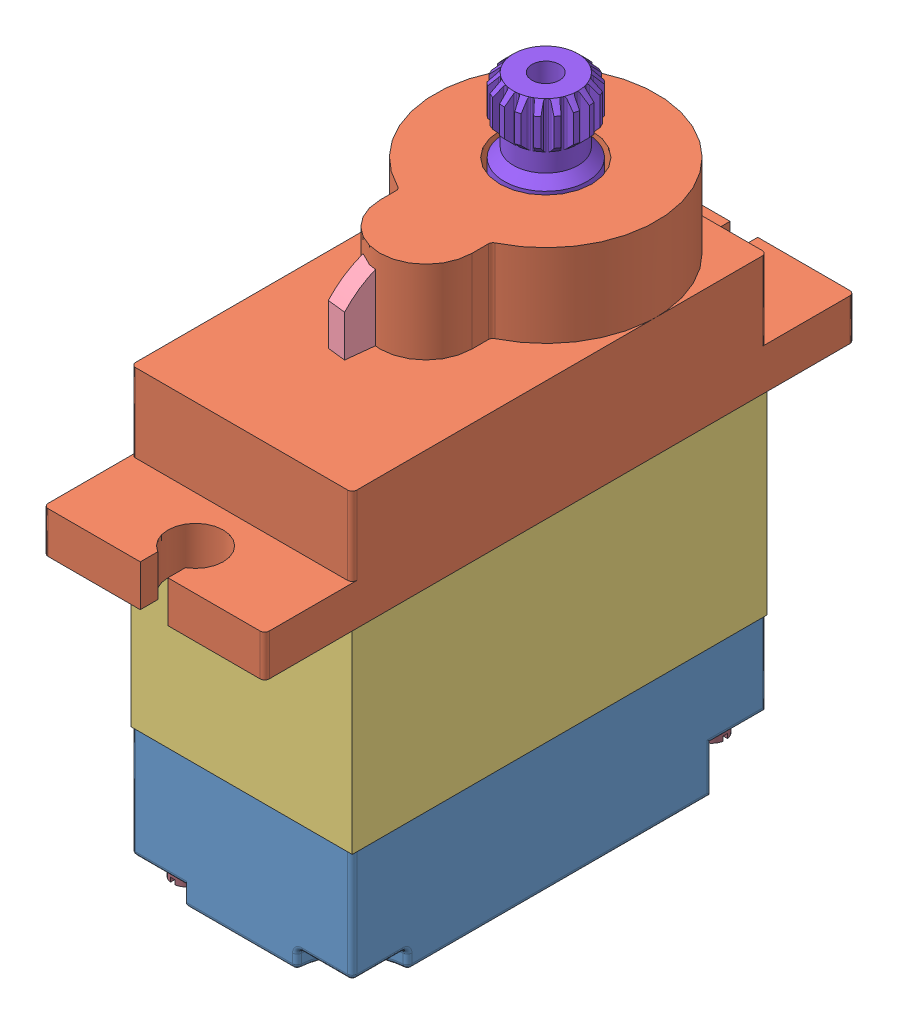
SolidWorks assembly MG90S, configuration Default. Lengths in mm.
Overall size (12 32.5 32).
19 component instances, 13 part files, 49 mates.
Components (placement in the parent):
- Part1-1: Part1 [Default] at (21.0878 -43.0505 -32.5824) x (0 0 -1) z (1 0 0) size (22.54 9 12)
- Part2-1: Part2 [Default] at (21.0878 -25.5505 -32.5824) x (0 0 -1) z (1 0 0) size (32 13 12)
- Part3-1: Part3 [Default] at (21.0878 -36.0505 -32.5824) x (0 0 -1) z (1 0 0) size (22.5 16 12)
- Motor_Body2-2: Motor_Body2 [Default] at (21.0878 -22.3005 -37.8324) x (0 -1 0) z (0.87496 0 0.484196) size (10 2 8)
- Motor_Body2-3: Motor_Body2 [Default] at (21.0878 -19.8005 -31.3324) x (0 -1 0) z (0.109568 0 -0.993979) size (10 2 8)
- Motor_Body2-6: Motor_Body2 [Default] at (21.0878 -19.8005 -37.8324) x (0 1 0) z (-0.993238 0 0.116099) size (10 2 8)
- Motor_Body2-7: Motor_Body2 [Default] at (21.0878 -25.0505 -31.3324) x (0 1 0) z (0.977188 0 0.212376) size (10 2 8)
- Motor_Body2-8: Motor_Body2 [Default] at (21.0878 -23.8005 -31.3324) x (0 1 0) z (0.977188 0 0.212376) size (10 2 8)
- gear3-1: gear3 [Default] at (21.0878 -22.3005 -37.8324) x (0.87496 0 0.484196) z (-0.484196 0 0.87496) size (3.98 2.5 3.92)
- gear1-2: gear1 [Default] at (21.0878 -19.8005 -31.3324) x (0.109568 0 -0.993979) z (0.993979 0 0.109568) size (3.96 2.5 3.87)
- gear2-2: gear2 [Default] at (21.0878 -26.3005 -26.3324) x (0.891105 0 -0.453797) z (0.453797 0 0.891105) size (2.5 2.5 2.5)
- Part4-1: Part4 [Default] at (21.0878 -17.0505 -37.8324) x (0.993238 0 -0.116099) z (0.116099 0 0.993238) size (4.5 6.5 4.5)
- Motor_Body-1: Motor_Body [Default] at (21.0878 -26.5505 -26.3324) x (-1 0 0) z (0 0 1) size (10 14.25 8)
- Motor_Body2-1: Motor_Body2 [Default] at (21.0878 -39.0505 -26.3324) size (10 2 8)
- cilinder2-1: cilinder2 [Default] at (21.0878 -31.8005 -37.8324) x (0.116099 0 0.993238) z (-0.993238 0 0.116099) size (1.5 15 1.5)
- cilinder1-1: cilinder1 [Default] at (21.0878 -27.3005 -31.3324) x (0.109568 0 -0.993979) z (0.993979 0 0.109568) size (1.25 12 1.25)
- Part5-1: Part5 [Default] at (21.0878 -40.0505 -32.0824) x (0 0 -1) z (1 0 0) size (19.28 16 10.15)
- Part6-1: Part6 [Default] at (16.5878 -42.0505 -22.8324) size (1.5 21 1.5)
- Part6-2: Part6 [Default] at (25.5878 -40.5505 -42.3324) size (1.5 21 1.5)
Mates (geometry in assembly coordinates):
- Parallel1: parallel aligned: plane of Part1-1 through (21.0878 -43.0505 -32.5824) normal (0 1 0)
- Concentric8: concentric: cylinder of Motor_Body2-7 through (29.1515 24.9496 -24.0125) axis (0 -1 0) radius 0.625; cylinder of Motor_Body2-8 through (29.1515 26.1996 -24.0125) axis (0 -1 0) radius 0.625
- Coincident3: coincident: plane of Motor_Body2-7 through (29.1515 -23.8005 -24.0125) normal (0 1 0); plane of Motor_Body2-8 through (29.1515 -23.8005 -24.0125) normal (0 -1 0)
- Parallel4: parallel aligned: plane of Motor_Body2-7 through (21.0878 -25.0505 -31.3324) normal (-0.212376 0 0.977188); plane of Motor_Body2-8 through (21.0878 -23.8005 -31.3324) normal (-0.212376 0 0.977188)
- Concentric9: concentric: cylinder of Motor_Body2-3 through (29.1515 -69.8005 -24.0125) axis (0 1 0) radius 0.625; cylinder of Motor_Body2-8 through (29.1515 26.1996 -24.0125) axis (0 -1 0) radius 0.625
- Concentric15: concentric: cylinder of Motor_Body2-2 through (31.0063 -72.3005 -30.2423) axis (0 1 0) radius 0.75; cylinder of gear3-1 through (31.0063 -19.8005 -30.2423) axis (0 -1 0) radius 0.75
- Coincident6: coincident: plane of Motor_Body2-2 through (31.0063 -22.3005 -30.2423) normal (0 1 0); plane of gear3-1 through (31.0063 -22.3005 -30.2423) normal (0 -1 0)
- Coincident7: coincident: plane of Motor_Body2-3 through (29.1515 -19.8005 -24.0125) normal (0 1 0); plane of gear1-2 through (29.1515 -19.8005 -24.0125) normal (0 -1 0)
- Concentric16: concentric: cylinder of Motor_Body2-3 through (29.1515 -69.8005 -24.0125) axis (0 1 0) radius 0.625; cylinder of gear1-2 through (29.1515 -17.3005 -24.0125) axis (0 -1 0) radius 0.625
- Concentric17: concentric: cylinder of Motor_Body2-2 through (31.0063 -72.3005 -30.2423) axis (0 1 0) radius 0.75; cylinder of Motor_Body2-6 through (31.0063 30.1996 -30.2423) axis (0 -1 0) radius 0.75
- Concentric18: concentric: cylinder of Part2-1 through (21.0878 -15.5505 -37.8324) axis (0 1 0) radius 2.5; cylinder of ? through (31.0063 -72.3005 -30.2423) axis (0 1 0) radius 0.75
- Concentric19: concentric: cylinder of Part2-1 through (21.0878 -15.3005 -31.3324) axis (0 -1 0) radius 0.625; cylinder of ? through (29.1515 24.9496 -24.0125) axis (0 -1 0) radius 0.625
- Coincident8: coincident: plane of Motor_Body2-3 through (29.1515 -21.8005 -24.0125) normal (0 -1 0); plane of Motor_Body2-8 through (29.1515 -21.8005 -24.0125) normal (0 1 0)
- Coincident9: coincident: plane of Motor_Body2-6 through (31.0063 -19.8005 -30.2423) normal (0 -1 0); plane of gear3-1 through (31.0063 -19.8005 -30.2423) normal (0 1 0)
- Coincident10: coincident: plane of Motor_Body2-2 through (31.0063 -23.8005 -30.2423) normal (0 -1 0); plane of Motor_Body2-7 through (29.1515 -23.8005 -24.0125) normal (0 1 0)
- Concentric21: concentric: cylinder of Motor_Body2-7 through (29.1515 24.9496 -24.0125) axis (0 -1 0) radius 0.625; cylinder of cilinder1-1 through (29.1515 -15.3005 -24.0125) axis (0 -1 0) radius 0.625
- Coincident16: coincident anti-aligned: plane of Part1-1 through (21.0878 -36.0505 -32.5824) normal (0 1 0); plane of Part3-1 through (21.0878 -36.0505 -32.5824) normal (0 -1 0)
- Coincident17: coincident aligned: plane of Part1-1 through (15.0878 -36.0505 -43.8324) normal (-1 0 0); plane of Part3-1 through (15.0878 -25.5505 -43.8324) normal (-1 0 0)
- Coincident18: coincident aligned: plane of Part1-1 through (27.0878 -36.0505 -43.8324) normal (0 0 -1); plane of Part3-1 through (27.0878 -25.5505 -43.8324) normal (0 0 -1)
- Concentric23: concentric aligned: cylinder of Part2-1 through (21.0878 -15.5505 -37.8324) axis (0 1 0) radius 2.5; cylinder of Part3-1 through (21.0878 -26.5505 -37.8324) axis (0 1 0) radius 0.75
- Coincident19: coincident anti-aligned: plane of Part2-1 through (21.0878 -25.5505 -32.5824) normal (0 -1 0); plane of Part3-1 through (21.0878 -25.5505 -32.5824) normal (0 1 0)
- Coincident20: coincident aligned: plane of Part2-1 through (27.0878 -19.0505 -43.8324) normal (1 0 0); plane of Part3-1 through (27.0878 -25.5505 -43.8324) normal (1 0 0)
- Coincident21: coincident anti-aligned: plane of Part2-1 through (21.0878 -15.3005 -31.3324) normal (0 -1 0); plane of cilinder1-1 through (21.0878 -15.3005 -31.3324) normal (0 1 0)
- Coincident22: coincident: plane of Part3-1 through (21.0878 -25.0505 -31.3324) normal (0 1 0); plane of ? through (29.1515 -25.0505 -24.0125) normal (0 -1 0)
- Concentric24: concentric: cylinder of Motor_Body2-6 through (31.0063 30.1996 -30.2423) axis (0 -1 0) radius 0.75; cylinder of cilinder2-1 through (31.0063 -16.8005 -30.2423) axis (0 -1 0) radius 0.75
- Distance2: distance = 3 mm: plane of Motor_Body2-6 through (21.0878 -19.8005 -37.8324) normal (0 -1 0); plane of cilinder2-1 through (21.0878 -16.8005 -37.8324) normal (0 1 0)
- Coincident23: coincident anti-aligned: plane of Motor_Body2-3 through (21.0878 -19.8005 -31.3324) normal (-0.993979 0 -0.109568); plane of cilinder1-1 through (21.0878 -27.3005 -31.3324) normal (0.993979 0 0.109568)
- Coincident24: coincident aligned: plane of Motor_Body2-6 through (21.0878 -19.8005 -37.8324) normal (-0.993238 0 0.116099); plane of cilinder2-1 through (21.0878 -31.8005 -37.8324) normal (-0.993238 0 0.116099)
- Parallel8: parallel anti-aligned: plane of Motor_Body2-3 through (21.0878 -19.8005 -31.3324) normal (-0.993979 0 -0.109568); plane of gear1-2 through (21.0878 -19.8005 -31.3324) normal (0.993979 0 0.109568)
- Parallel9: parallel anti-aligned: plane of Motor_Body2-2 through (21.0878 -22.3005 -37.8324) normal (0.484196 0 -0.87496); plane of gear3-1 through (21.0878 -22.3005 -37.8324) normal (-0.484196 0 0.87496)
- Concentric25: concentric anti-aligned: cylinder of Part2-1 through (21.0878 -15.5505 -37.8324) axis (0 1 0) radius 2.5; cylinder of Part4-1 through (21.0878 -10.5505 -37.8324) axis (0 -1 0) radius 2.25
- Coincident25: coincident: plane of Motor_Body2-6 through (31.0063 -17.0505 -30.2423) normal (0 1 0); plane of Part4-1 through (31.0063 -17.0505 -30.2423) normal (0 -1 0)
- Parallel10: parallel anti-aligned: plane of Motor_Body2-6 through (21.0878 -19.8005 -37.8324) normal (-0.116099 0 -0.993238); plane of Part4-1 through (21.0878 -17.0505 -37.8324) normal (0.116099 0 0.993238)
- Concentric26: concentric anti-aligned: cylinder of Motor_Body-1 through (21.0878 -38.0505 -26.3324) axis (0 1 0) radius 5; cylinder of Motor_Body2-1 through (21.0878 -38.0505 -26.3324) axis (0 -1 0) radius 5
- Coincident26: coincident anti-aligned: plane of Motor_Body-1 through (21.0878 -38.0505 -26.3324) normal (0 -1 0); plane of Motor_Body2-1 through (21.0878 -38.0505 -26.3324) normal (0 1 0)
- Coincident27: coincident anti-aligned: plane of Motor_Body-1 through (25.5878 -38.0505 -25.8324) normal (0 0 -1); plane of Motor_Body2-1 through (21.0878 -37.0505 -25.8324) normal (0 0 1)
- Concentric27: concentric aligned: cylinder of Part3-1 through (21.0878 -26.5505 -26.3324) axis (0 1 0) radius 2; cylinder of Motor_Body-1 through (21.0878 -38.0505 -26.3324) axis (0 1 0) radius 5
- Coincident28: coincident anti-aligned: plane of Part3-1 through (26.0878 -25.5505 -22.3324) normal (0 0 -1); plane of Motor_Body-1 through (24.0878 -38.0505 -22.3324) normal (0 0 1)
- Coincident29: coincident aligned: circle of Part3-1; plane of Motor_Body-1 through (21.0878 -26.5505 -26.3324) normal (0 1 0)
- Concentric28: concentric aligned: cylinder of Motor_Body-1 through (21.0878 -23.8005 -26.3324) axis (0 -1 0) radius 0.25; cylinder of gear2-2 through (21.0878 -23.8005 -26.3324) axis (0 -1 0) radius 0.25
- Coincident30: coincident aligned: plane of Motor_Body-1 through (21.0878 -23.8005 -26.3324) normal (0 1 0); plane of gear2-2 through (21.0878 -23.8005 -26.3324) normal (0 1 0)
- Coincident31: coincident anti-aligned: plane of Motor_Body2-1 through (21.0878 -39.0505 -26.3324) normal (0 -1 0); plane of Part5-1 through (16.0878 -39.0505 -23.3324) normal (0 1 0)
- Distance3: distance = 1 mm aligned: plane of Part5-1 through (24.5878 -39.0505 -23.3324) normal (0 0 1); plane of Motor_Body2-1 through (18.0878 -38.0505 -22.3324) normal (0 0 1)
- Tangent1: tangent aligned: cylinder of Motor_Body2-1 through (21.0878 -38.0505 -26.3324) axis (0 -1 0) radius 5; plane of Part5-1 through (26.0878 -39.0505 -40.8324) normal (1 0 0)
- Concentric29: concentric aligned: cylinder of Part1-1 through (16.5878 -33.2221 -22.8324) axis (0 -1 0) radius 0.5; cylinder of Part6-1 through (16.5878 -22.0505 -22.8324) axis (0 -1 0) radius 0.5
- Coincident32: coincident anti-aligned: plane of Part1-1 through (15.0878 -42.0505 -21.3324) normal (0 -1 0); plane of Part6-1 through (16.5878 -42.0505 -22.8324) normal (0 1 0)
- Concentric30: concentric aligned: cylinder of Part1-1 through (25.5878 -33.9292 -42.3324) axis (0 -1 0) radius 0.5; cylinder of Part6-2 through (25.5878 -20.5505 -42.3324) axis (0 -1 0) radius 0.5
- Coincident33: coincident anti-aligned: plane of Part1-1 through (27.0878 -40.5505 -43.8324) normal (0 -1 0); plane of Part6-2 through (25.5878 -40.5505 -42.3324) normal (0 1 0)
- Parallel11: parallel aligned: plane of Part1-1 through (21.0878 -43.0505 -32.5824) normal (1 0 0)
